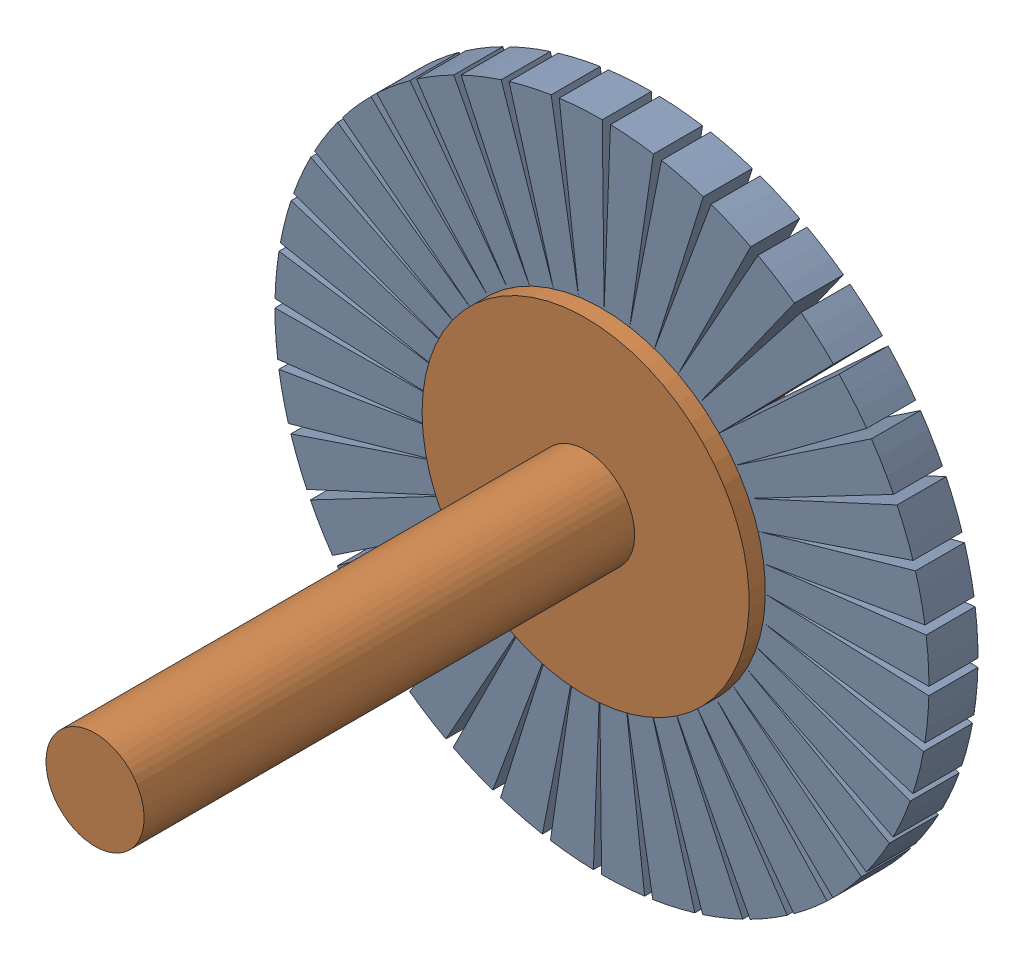
SolidWorks assembly complete borstel, configuration Default. Lengths in mm.
Overall size (40.02 40.02 35).
2 component instances, 2 part files, 2 mates.
Components (placement in the parent):
- draad-1: draad [Default] at (0.3938 15.7431 13.2639) size (40.02 40.02 3.02)
- frame-1: frame [Default] at (0.3938 15.7431 12.2639) x (1 0 0) z (0 -1 0) size (20 35 20)
Mates (geometry in assembly coordinates):
- Coincident1: coincident: plane of draad-1 through (0.3938 15.7431 16.2639) normal (0 0 1); plane of frame-1 through (5.3938 15.7431 16.2639) normal (0 0 -1)
- Concentric1: concentric anti-aligned: cylinder of draad-1 through (0.3938 15.7431 16.2639) axis (0 0 -1) radius 20; cylinder of frame-1 through (0.3938 15.7431 17.2639) axis (0 0 1) radius 10
